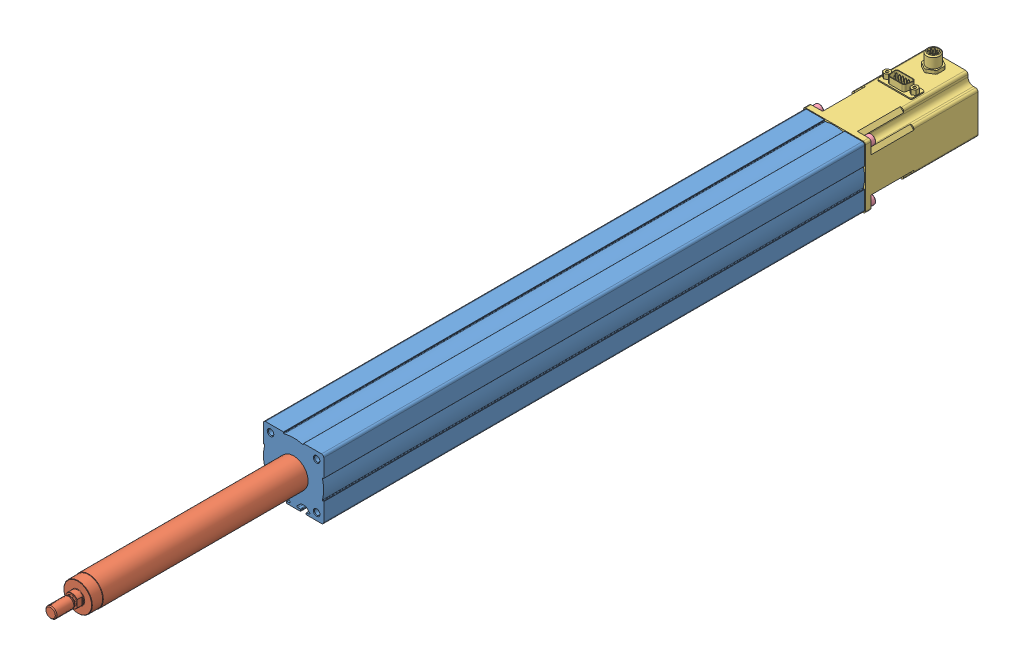
SolidWorks assembly Actuator 300mm, configuration Default. Lengths in mm.
Overall size (56.4 69.4 816.45).
7 component instances, 4 part files, 19 mates.
Components (placement in the parent):
- 1472887 EPCO-40-30000_z---(0)-1: 1472887 EPCO-40-30000_z---(0) [Default] at origin size (55 55 492.7)
- 1472887 EPCO-40-300_k---(1_0)-1: 1472887 EPCO-40-300_k---(1_0) [Default] at (0 0 180.7542) size (40 40 455.5)
- 1464059 EMMS-ST-57-SS-SE-G2-1: 1464059 EMMS-ST-57-SS-SE-G2 [Default] at (0 0 -492.7) size (56.4 69.4 116.1)
- DIN-912 - M5x12(F)-1: DIN-912 - M5x12(F) [Default] at (23.57 23.57 -497.7) x (1 0 0) z (0 1 0) size (8.5 17.23 8.5)
- DIN-912 - M5x12(F)-2: DIN-912 - M5x12(F) [Default] at (-23.57 23.57 -497.7) x (1 0 0) z (0 1 0) size (8.5 17.23 8.5)
- DIN-912 - M5x12(F)-3: DIN-912 - M5x12(F) [Default] at (-23.57 -23.57 -497.7) x (1 0 0) z (0 1 0) size (8.5 17.23 8.5)
- DIN-912 - M5x12(F)-4: DIN-912 - M5x12(F) [Default] at (23.57 -23.57 -497.7) x (1 0 0) z (0 1 0) size (8.5 17.23 8.5)
Mates (geometry in assembly coordinates):
- LimitDistance1: limit distance = 180.7542 mm anti-aligned: plane of 1472887 EPCO-40-30000_z---(0)-1 through (0 0 0) normal (0 0 1); plane of 1472887 EPCO-40-300_k---(1_0)-1 through (0 0 180.7542) normal (0 0 -1)
- Coincident1: coincident anti-aligned: line of 1472887 EPCO-40-30000_z---(0)-1 through (0 0 80.9) axis (0 0 -1); line of 1472887 EPCO-40-300_k---(1_0)-1 through (0 0 99.8542) axis (0 0 1)
- Angle3: planar angle = 0 rad aligned: plane of 1472887 EPCO-40-300_k---(1_0)-1 through (0 0 180.7542) normal (1 0 0); plane of 1472887 EPCO-40-30000_z---(0)-1 through (0 0 0) normal (1 0 0)
- Distance2: distance = 0 mm anti-aligned: plane of 1472887 EPCO-40-30000_z---(0)-1 through (0 0 -492.7) normal (0 0 1); plane of 1464059 EMMS-ST-57-SS-SE-G2-1 through (0 0 -492.7) normal (0 0 -1)
- Coincident3: coincident anti-aligned: line of 1472887 EPCO-40-30000_z---(0)-1 through (0 0 80.9) axis (0 0 -1); line of 1464059 EMMS-ST-57-SS-SE-G2-1 through (0 0 -573.6) axis (0 0 1)
- Angle9: planar angle = 0 rad aligned: plane of 1464059 EMMS-ST-57-SS-SE-G2-1 through (0 0 -492.7) normal (1 0 0); plane of 1472887 EPCO-40-30000_z---(0)-1 through (0 0 0) normal (1 0 0)
- Distance3: distance = 0 mm anti-aligned: plane of 1464059 EMMS-ST-57-SS-SE-G2-1 through (0 0 -497.7) normal (0 0 1); plane of DIN-912 - M5x12(F)-1 through (23.57 23.57 -497.7) normal (0 0 -1)
- Coincident4: coincident anti-aligned: line of 1464059 EMMS-ST-57-SS-SE-G2-1 through (23.57 23.57 -411.8) axis (0 0 -1); line of DIN-912 - M5x12(F)-1 through (23.57 23.57 -547.7) axis (0 0 1)
- Angle12: planar angle = 0 rad aligned: plane of DIN-912 - M5x12(F)-1 through (23.57 23.57 -497.7) normal (1 0 0); plane of 1464059 EMMS-ST-57-SS-SE-G2-1 through (23.57 0 -492.7) normal (1 0 0)
- Distance4: distance = 0 mm anti-aligned: plane of 1464059 EMMS-ST-57-SS-SE-G2-1 through (0 0 -497.7) normal (0 0 1); plane of DIN-912 - M5x12(F)-2 through (-23.57 23.57 -497.7) normal (0 0 -1)
- Coincident5: coincident anti-aligned: line of 1464059 EMMS-ST-57-SS-SE-G2-1 through (-23.57 23.57 -411.8) axis (0 0 -1); line of DIN-912 - M5x12(F)-2 through (-23.57 23.57 -547.7) axis (0 0 1)
- Angle15: planar angle = 0 rad aligned: plane of DIN-912 - M5x12(F)-2 through (-23.57 23.57 -497.7) normal (1 0 0); plane of 1464059 EMMS-ST-57-SS-SE-G2-1 through (-23.57 0 -492.7) normal (1 0 0)
- Distance5: distance = 0 mm anti-aligned: plane of 1464059 EMMS-ST-57-SS-SE-G2-1 through (0 0 -497.7) normal (0 0 1); plane of DIN-912 - M5x12(F)-3 through (-23.57 -23.57 -497.7) normal (0 0 -1)
- Coincident6: coincident anti-aligned: line of 1464059 EMMS-ST-57-SS-SE-G2-1 through (-23.57 -23.57 -411.8) axis (0 0 -1); line of DIN-912 - M5x12(F)-3 through (-23.57 -23.57 -547.7) axis (0 0 1)
- Angle18: planar angle = 0 rad aligned: plane of DIN-912 - M5x12(F)-3 through (-23.57 -23.57 -497.7) normal (1 0 0); plane of 1464059 EMMS-ST-57-SS-SE-G2-1 through (-23.57 0 -492.7) normal (1 0 0)
- Distance6: distance = 0 mm anti-aligned: plane of 1464059 EMMS-ST-57-SS-SE-G2-1 through (0 0 -497.7) normal (0 0 1); plane of DIN-912 - M5x12(F)-4 through (23.57 -23.57 -497.7) normal (0 0 -1)
- Coincident7: coincident anti-aligned: line of 1464059 EMMS-ST-57-SS-SE-G2-1 through (23.57 -23.57 -411.8) axis (0 0 -1); line of DIN-912 - M5x12(F)-4 through (23.57 -23.57 -547.7) axis (0 0 1)
- Angle21: planar angle = 0 rad aligned: plane of DIN-912 - M5x12(F)-4 through (23.57 -23.57 -497.7) normal (1 0 0); plane of 1464059 EMMS-ST-57-SS-SE-G2-1 through (23.57 0 -492.7) normal (1 0 0)
- Distance7: distance = 315.8 mm aligned: plane of 1472887 EPCO-40-300_k---(1_0)-1 through (0 6.4 196.5542) normal (0 0 1); plane of 1472887 EPCO-40-30000_z---(0)-1 through (-25.5 -25.5 0) normal (0 0 1)
